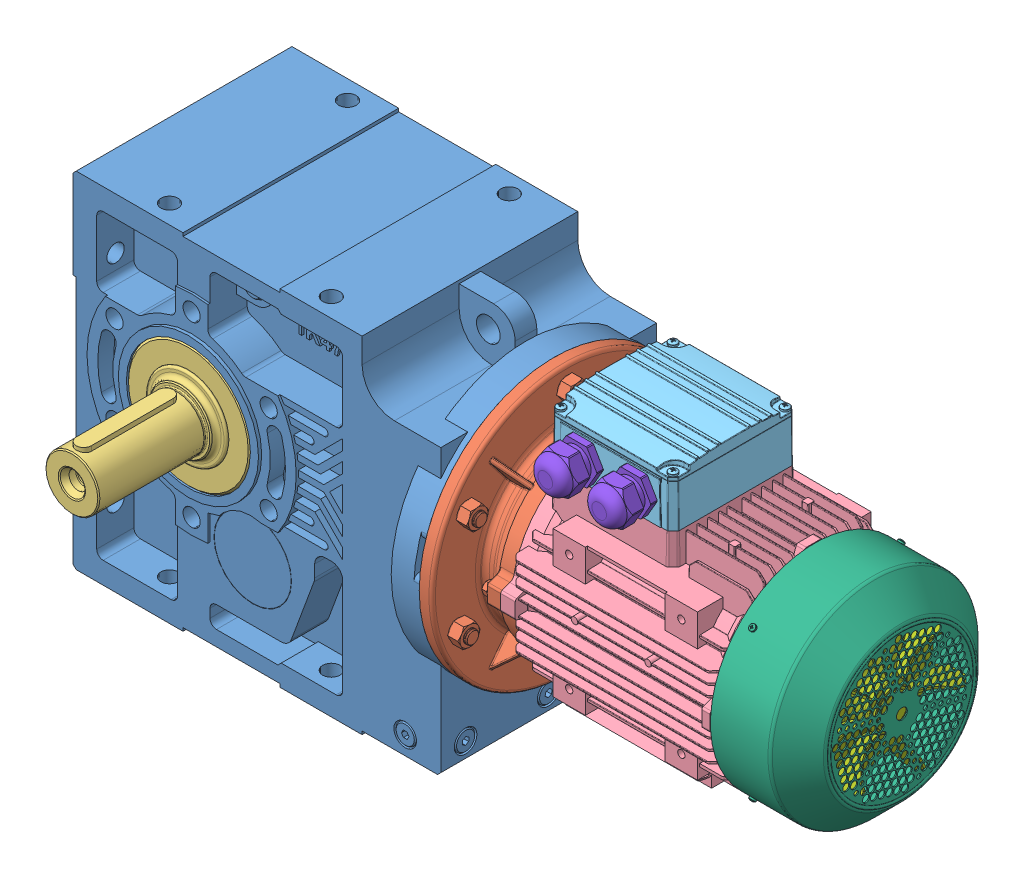
SolidWorks assembly SHRPRO-V1 3kW Motor KR 473 L3E100L, configuration Predeterminado. Lengths in mm.
Overall size (669.3 320 352.8).
8 component instances, 8 part files, 0 mates.
Components (placement in the parent):
- K473_Varsay_lan-1: K473_Varsay_lan [Predeterminado] at (-1060.9999 -980 -1000) size (346 320 250)
- 433E100_Varsay_lan-1: 433E100_Varsay_lan [Predeterminado] at (-780.4999 -993 -1000) x (0 0 1) z (-1 0 0) size (250 250 46.5)
- ML36A_L_Varsay_lan-1: ML36A_L_Varsay_lan [Predeterminado] at (-1060.9999 -980 -892.5) x (0 0 1) z (-1 0 0) size (318 115 115)
- 3E100L_DA_Varsay_lan(2)-1: 3E100L_DA_Varsay_lan(2) [Predeterminado] at (-680.4999 -993 -1000) x (0 0 1) z (-1 0 0) size (192 192 200)
- KL_3E100_Varsay_lan(2)-1: KL_3E100_Varsay_lan(2) [Predeterminado] at (-716.6499 -897 -1000) x (0 0 1) z (-1 0 0) size (116.45 51.17 115.89)
- T_3E100_1_Varsay_lan(2)-1: T_3E100_1_Varsay_lan(2) [Predeterminado] at (-585.4999 -993 -1000) x (-1 0 0) z (0 -0.707107 -0.707107) size (81.8 197.71 197.71)
- EF2100A_Varsay_lan(2)-1: EF2100A_Varsay_lan(2) [Predeterminado] at (-580.4999 -993 -1000) size (69 193.07 193.07)
- RK_3E100_Varsay_lan(2)-1: RK_3E100_Varsay_lan(2) [Predeterminado] at (-741.6499 -877 -906.5) x (-1 0 0) z (0 0 -1) size (87.5 33.01 45)
